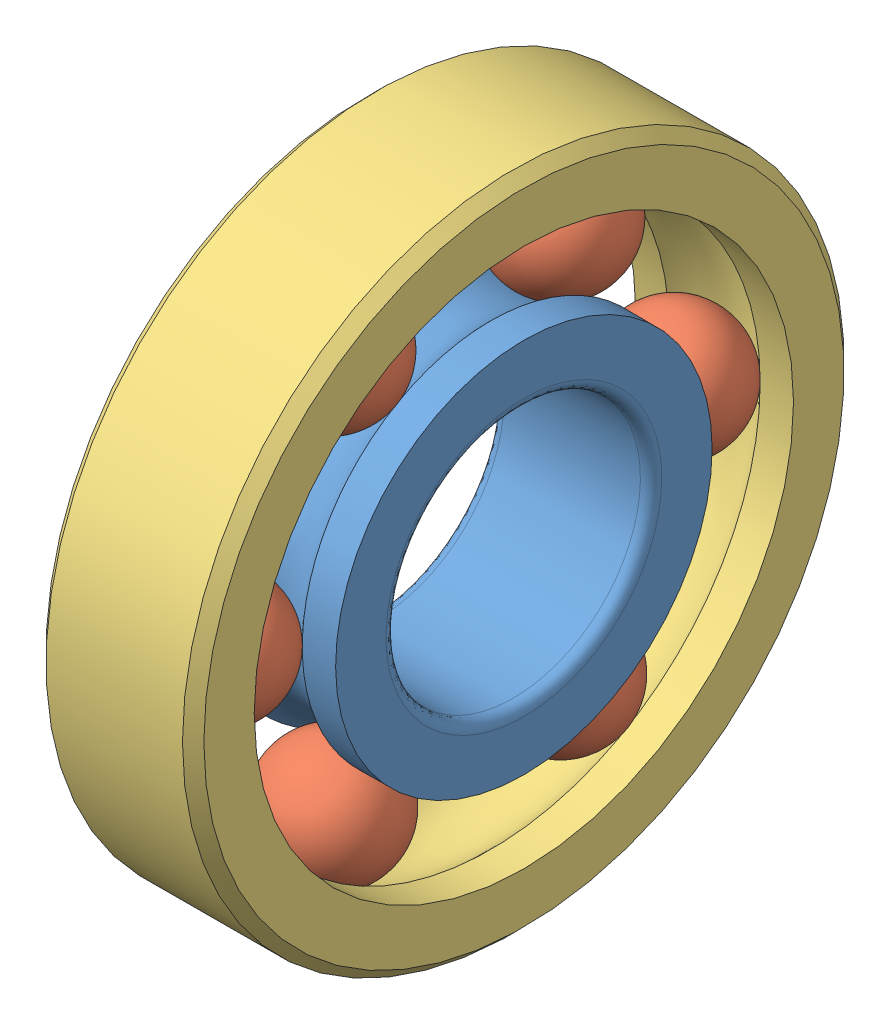
SolidWorks assembly Assem4, configuration Default. Lengths in mm.
Overall size (31 130 130).
8 component instances, 3 part files, 5 mates.
Components (placement in the parent):
- inner ring-1: inner ring [Default] at (-1.1476 45.6956 67.1738) x (1 0 0) z (0 0.999989 0.004731) size (31 74 74)
- ball-1: ball [Default] at (-1.1476 45.4827 112.1733) x (1 0 0) z (0 0.999989 0.004731) size (24 24 24)
- outer ring-1: outer ring [Default] at (-1.1476 45.6956 67.1738) size (31 130 130)
- ball-2: ball [Default] at (-1.1476 84.5599 89.8579) x (1 0 0) z (0 0.504091 -0.86365) size (24 24 24)
- ball-3: ball [Default] at (-1.1476 84.7728 44.8584) x (1 0 0) z (0 -0.495897 -0.868381) size (24 24 24)
- ball-4: ball [Default] at (-1.1476 45.9085 22.1743) x (1 0 0) z (0 -0.999989 -0.004731) size (24 24 24)
- ball-5: ball [Default] at (-1.1476 6.8313 44.4897) x (1 0 0) z (0 -0.504091 0.86365) size (24 24 24)
- ball-6: ball [Default] at (-1.1476 6.6185 89.4892) x (1 0 0) z (0 0.495897 0.868381) size (24 24 24)
Mates (geometry in assembly coordinates):
- Concentric1: concentric aligned: cylinder of inner ring-1 through (-13.0169 45.6956 67.1738) axis (-1 0 0) radius 25; cylinder of outer ring-1 through (-48.513 45.6956 67.1738) axis (-1 0 0) radius 65
- Width1: width aligned: plane of outer ring-1 through (14.3524 110.6956 67.1738) normal (1 0 0); plane of outer ring-1 through (-16.6476 110.6956 67.1738) normal (-1 0 0); plane of inner ring-1 through (14.3524 45.8706 30.1742) normal (1 0 0); plane of inner ring-1 through (-16.6476 45.8706 30.1742) normal (-1 0 0)
- Coincident1: coincident aligned: plane of inner ring-1 through (-1.1476 45.6956 67.1738) normal (0 0.999989 0.004731); plane of ball-1 through (-1.1476 45.4827 112.1733) normal (0 0.999989 0.004731)
- Coincident2: coincident aligned: plane of inner ring-1 through (-1.1476 45.6956 67.1738) normal (1 0 0); plane of ball-1 through (-1.1476 45.4827 112.1733) normal (1 0 0)
- Tangent1: tangent anti-aligned: torus of inner ring-1; sphere of ball-1
